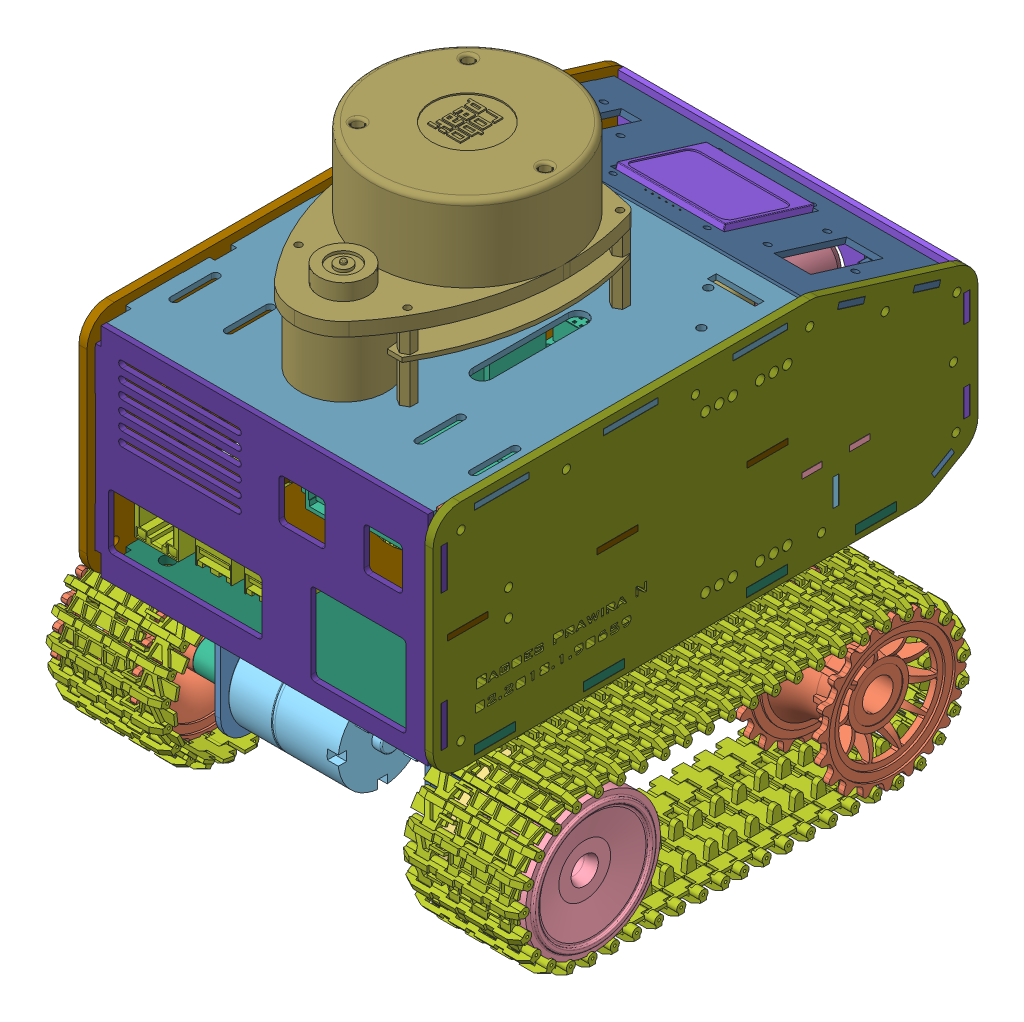
SolidWorks assembly UiRS.2 - Rover Explorer 1, configuration Default. Lengths in mm.
Overall size (173.8 212.34 209.38).
48 component instances, 30 part files, 0 mates.
Components (placement in the parent):
- Mini TP101 Smart Tank Chassis-1: Mini TP101 Smart Tank Chassis [Default] at (12.832 -28.5956 68.0909) size (173.8 71.3 180.56)
  - Base Frame-1: Base Frame [Default] at (60.6644 78.7904 111.7014) size (79 37 140)
  - DriverWheel-1: DriverWheel [Default] at (-9.5356 57.0404 166.6012) x (1 0 0) z (0 0.924225 0.381849) size (31.4 54.59 54.59)
  - DriverWheel-2: DriverWheel [Default] at (130.8644 57.0404 56.8017) x (-1 0 0) z (0 -0.057411 -0.998351) size (31.4 54.59 54.59)
  - FreeWheel_a-1: FreeWheel_a [Default] at (113.4144 57.1904 166.6014) x (0 0.96658 -0.256365) z (0 0.256365 0.96658) size (49.65 25.15 49.65)
  - FreeWheel_b-1: FreeWheel_b [Default] at (120.0644 57.1904 166.6014) x (0 1 0) z (0 0 1) size (49.6 27.5 49.6)
  - HTE-33GB-520-18.7 Motor-1: HTE-33GB-520-18.7 Motor [Default] at (82.1644 57.0103 62.8016) x (0 -0.999987 -0.005025) z (-1 0 0) size (32.75 32.75 56.05)
  - Motor Horn-1: Motor Horn [Default] at (100.6644 57.0404 56.8017) x (1 0 0) z (0 0.057411 0.998351) size (23.01 11.9 11.9)
  - FreeWheel_a-2: FreeWheel_a [Default] at (7.9144 57.1904 56.8014) x (0 -0.703844 0.710354) z (0 0.710354 0.703844) size (49.65 25.15 49.65)
  - FreeWheel_b-2: FreeWheel_b [Default] at (1.2644 57.1904 56.8014) x (0 -0.876069 -0.482185) z (0 -0.482185 0.876069) size (49.6 27.5 49.6)
  - HTE-33GB-520-18.7 Motor-2: HTE-33GB-520-18.7 Motor [Default] at (39.1644 57.0103 160.6013) x (0 -0.999987 0.005025) z (1 0 0) size (32.75 32.75 56.05)
  - Motor Horn-2: Motor Horn [Default] at (20.6644 57.0404 166.6012) x (-1 0 0) z (0 -0.924225 -0.381849) size (23.01 11.9 11.9)
  - SinglePart Crawler-1: SinglePart Crawler [Default] at (125.1144 31.4354 111.7366) x (1 0 0) z (0 0.001366 0.999999) size (44.5 59.42 169.22)
  - SinglePart Crawler-2: SinglePart Crawler [Default] at (-3.7856 31.4354 111.6663) x (-1 0 0) z (0 0.001366 -0.999999) size (44.5 59.42 169.22)
- Body Section-1: Body Section [Default] at (114.2586 36.5299 180.3392) x (-1 0 0) z (0 0 -1) size (130 85 200)
  - Body Depan-1: Body Depan [Default] at (40.7622 68.0273 103.7562) size (130 55 2)
  - Body Samping 2-1: Body Samping 2 [Default] at (104.2622 71.5273 7.8812) size (3 85 200)
  - Body Atas Miring-1: Body Atas Miring [Default] at (40.7622 101.2701 75.2562) x (1 0 0) z (0 -0.294645 0.955607) size (130 2 53.98)
  - Logitech c270 Assembly-1: Logitech c270 Assembly [Default] at (38.454 72.9146 8.8004) x (0.999997 0.002498 0) z (0 0 1) size (75.43 34.31 66.44)
    - Logitech c270c-1: Logitech c270c [Default] at (12.7536 -9.0803 49.7308) size (36.61 14.96 39.87)
    - Logitech c270b-1: Logitech c270b [Default] at (13.5036 -4.8303 73.6058) x (1 0 0) z (0 0 -1) size (42.07 20.83 48.65)
    - Logitech c270-1: Logitech c270 [Default] at (18.796 -4.893 93.9558) size (75.43 34.31 27.34)
  - Body Atas-1: Body Atas [Default] at (40.7622 109.9023 -19.4938) x (0 0 -1) z (1 0 0) size (134.75 2 130)
  - Body Bawah-1: Body Bawah [Default] at (40.7622 32.6648 0.5469) x (0 0 -1) z (1 0 0) size (174.83 3 130)
  - Body Samping-1: Body Samping [Default] at (-22.7378 71.5273 7.8812) size (3 85 200)
  - Body Back-1: Body Back [Default] at (40.7622 71.5273 -87.9938) x (-1 0 0) z (0 0 -1) size (130 80 2)
  - Middle Body-1: Middle Body [Default] at (40.7622 73.1523 -24.3688) x (0 0 1) z (-1 0 0) size (125 2 130)
  - Base GP-1: Base GP [Default] at (40.7622 37.8697 95.028) x (1 0 0) z (0 0.5 0.866025) size (130 2 12.5)
  - Jig Baut-1: Jig Baut [Default] at (-20.2378 34.2773 -81.8688) x (0 0 1) z (1 0 0) size (12 11.5 2)
  - Jig Baut-2: Jig Baut [Default] at (-20.2378 100.195 74.9247) x (0 0.294645 -0.955607) z (1 0 0) size (12 11.5 2)
  - Jig Baut-3: Jig Baut [Default] at (-20.2378 34.2773 50.4626) x (0 0 1) z (1 0 0) size (12 11.5 2)
  - Jig Baut-4: Jig Baut [Default] at (-20.2378 108.7773 4.1937) x (0 0 -1) z (1 0 0) size (12 11.5 2)
  - Jig Baut-5: Jig Baut [Default] at (-20.2378 108.7773 -43.1813) x (0 0 -1) z (1 0 0) size (12 11.5 2)
  - Jig Baut-6: Jig Baut [Default] at (-20.2378 108.7773 -81.8688) x (0 0 -1) z (1 0 0) size (12 11.5 2)
  - Jig Baut-7: Jig Baut [Default] at (-20.2378 68.0273 102.6312) x (0 1 0) z (1 0 0) size (12 11.5 2)
  - Jig Baut Double-1: Jig Baut Double [Default] at (-20.2378 72.1523 -64.3688) x (0 0 1) z (-1 0 0) size (12 19 2)
  - Base Camera-1: Base Camera [Default] at (40.7622 59.5573 55.7126) size (130 2 25)
  - Jig Base Camera-1: Jig Base Camera [Default] at (-21.2378 58.5573 55.7126) x (0 0 -1) z (1 0 0) size (2 18 23.2)
  - Jig Base Camera-2: Jig Base Camera [Default] at (102.7622 58.5573 55.7126) x (0 0 1) z (-1 0 0) size (2 18 23.2)
- ArduinoMega 2560-1: ArduinoMega 2560 [Default] at (98.7883 119.8458 205.058) x (0 0 1) z (0 -1 0) size (107.95 53.42 12.98)
- Raspberry Pi 3 UK-1: Raspberry Pi 3 UK [Default] at (44.4964 78.8448 215.8142) x (0 0 1) z (-1 0 0) size (91.72 19.96 57.54)
- Nokia_5110-3310_LCD_asm-1: Nokia_5110-3310_LCD_asm [Default] at (78.569 137.666 108.0424) x (1 0 0) z (0 0.294645 0.955607) size (43 14.16 45.65)
  - Nokia_5110-3310_LCD_breakout-1: Nokia_5110-3310_LCD_breakout [Default] at (-5.0727 0 -2.7886) x (-1 0 0) z (0 0 -1) size (43 4.67 45.65)
  - Pin Header 1x6 TH Pitch 2.54mm-1: Pin Header 1x6 TH Pitch 2.54mm [Default] at (1.2773 -1.0146 16.4339) x (-1 0 0) z (0 -1 0) size (15.24 2.54 12.7)
- PIRSLDASM-1: PIRSLDASM [Default] at (81.706 104.7639 66.5282) x (0 1 0) z (1 0 0) size (32 23.5 25)
  - sensor-1: sensor [Default] at (-0.2067 11.0548 34.2903) size (32 15 25)
  - lens-1: lens [Default] at (-0.2067 10.0548 34.2903) x (-1 0 0) z (0 0 1) size (24 19.5 24)
- [Komp] - Lidar-1: [Komp] - Lidar [Default] at (73.4964 172.0323 209.083) x (0 0 1) z (-1 0 0) size (98.5 57.7 70.02)
